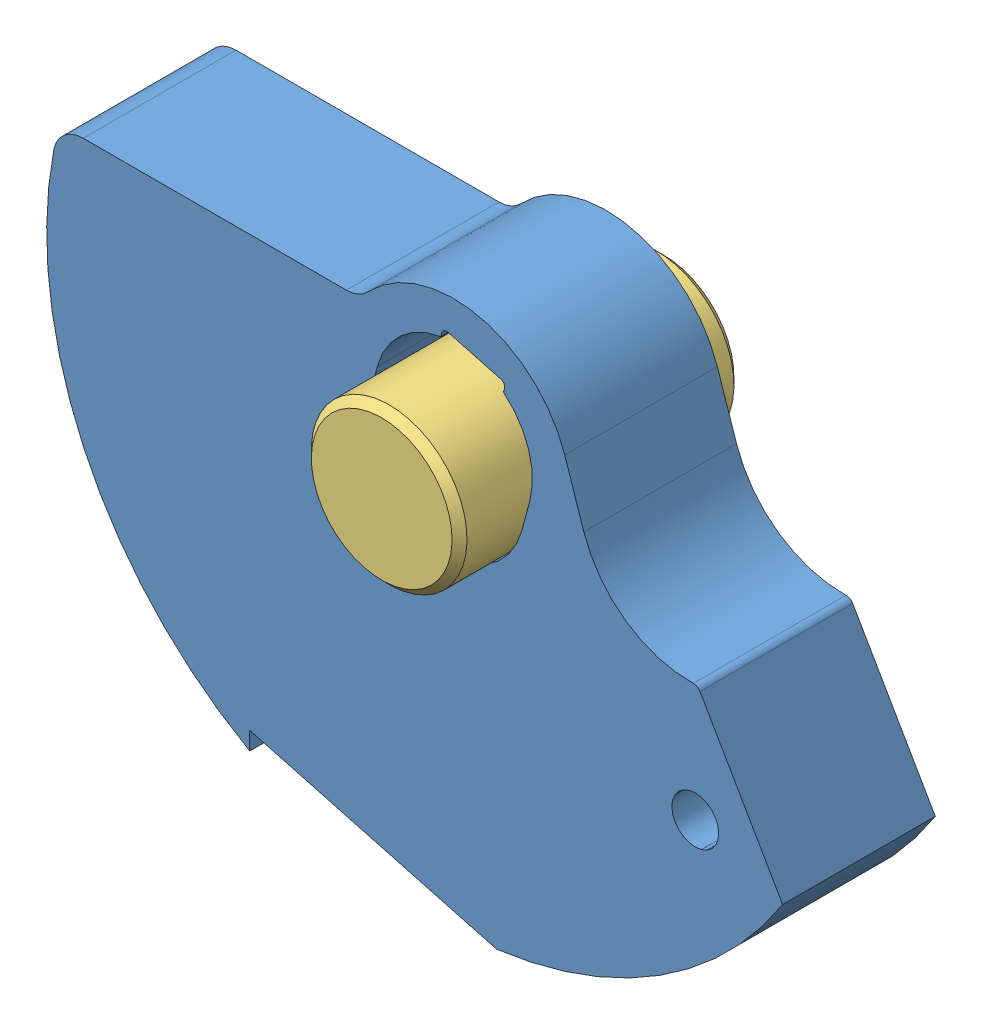
SolidWorks assembly 4106-1, configuration Default. Lengths in mm.
Overall size (37.47 27.59 14.35).
3 component instances, 3 part files, 6 mates.
Components (placement in the parent):
- 4106-1: 4106 [Default] at (24.5736 24.1411 23.586) size (37.47 27.59 7.77)
- 2979-1: 2979 [Default] at (23.433 19.8844 19.6998) x (0.258819 0.965926 0) z (0.911494 -0.244234 0.330949) size (11.38 3.26 3.28)
- 4105-1: 4105 [Default] at (24.5867 24.1902 26.8626) x (0.965926 -0.258819 0) z (0.258819 0.965926 0) size (7.92 14.35 7.92)
Mates (geometry in assembly coordinates):
- Distance1: distance = 3.8862 mm: plane of 4106-1 through (24.5736 24.1411 15.8136) normal (0 0 -1); line of 2979-1 through (26.2641 30.4502 19.6998) axis (-0.258819 -0.965926 0)
- Distance2: distance = 1.651 mm: plane of 4106-1 through (22.9788 24.5684 15.8136) normal (0.965926 -0.258819 0); line of 2979-1 through (26.2641 30.4502 19.6998) axis (-0.258819 -0.965926 0)
- Concentric1: concentric anti-aligned: line of 2979-1 through (26.2641 30.4502 19.6998) axis (-0.258819 -0.965926 0); cylinder of 4105-1 through (25.6139 28.0237 19.6998) axis (0.258819 0.965926 0) radius 1.7272
- Parallel1: parallel aligned: cylinder of 4106-1 through (24.5736 24.1411 15.8136) axis (0 0 1) radius 4.0132; cylinder of 4105-1 through (24.5867 24.1902 12.5116) axis (0 0 1) radius 3.9624
- Distance3: distance = 0 mm: cylinder of 4105-1 through (24.5867 24.1902 12.5116) axis (0 0 1) radius 3.9624; cylinder of 4106-1 through (24.5736 24.1411 15.8136) axis (0 0 1) radius 4.0132
- Coincident1: coincident anti-aligned: plane of 4106-1 through (26.033 29.5878 15.8136) normal (-0.258819 -0.965926 0); plane of 2979-1 through (26.033 29.5878 19.6998) normal (0.258819 0.965926 0)
